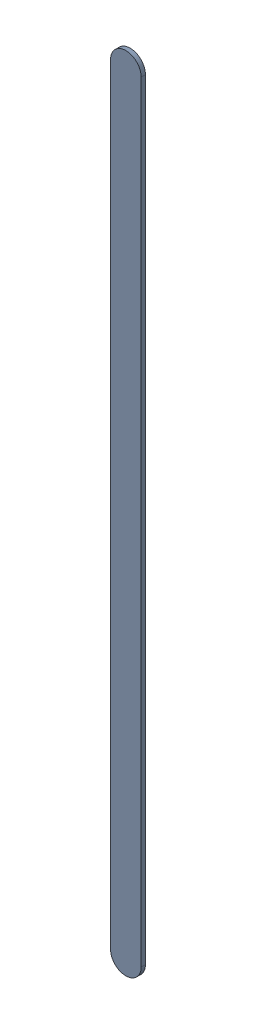
SolidWorks assembly Track (25.5mm,40.8mm)(25.5mm,47.2mm) on Bottom Layer, configuration Predeterminado. Lengths in mm.
Overall size (0.25 6.65 0.04).
2 component instances, 1 part files, 0 mates.
Components (placement in the parent):
- Track (25.5mm,40.8mm)(25.5mm,47.2mm) on Bottom Layer-1-1: Track (25.5mm,40.8mm)(25.5mm,47.2mm) on Bottom Layer-1 [Predeterminado] at (-68.317 -44.187 -0.4013) size (0.25 6.65 0.04)
  - Track (25.5mm,40.8mm)(25.5mm,47.2mm) on Bottom Layer-Part-1-1: Track (25.5mm,40.8mm)(25.5mm,47.2mm) on Bottom Layer-Part-1 [Predeterminado] at origin size (0.25 6.65 0.04)
